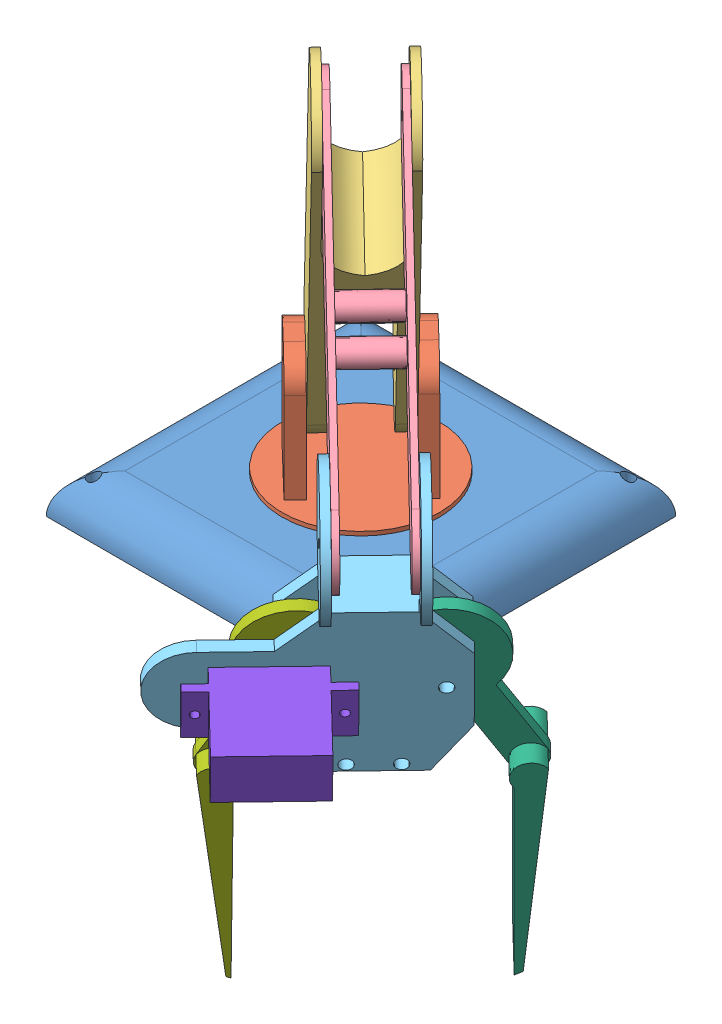
SolidWorks assembly ARM_only, configuration Default. Lengths in mm.
Overall size (206.23 165.3 199.03).
9 component instances, 8 part files, 10 mates.
Components (placement in the parent):
- arm_base-1: arm_base [Default] at (38.6443 32.0455 63.3645) size (80 10 80)
- arm_shoulder-1: arm_shoulder [Default] at (27.657 34.0455 61.3737) x (0.720928 0 0.69301) z (-0.69301 0 0.720928) size (69.78 39 69.78)
- arm_bicep-1: arm_bicep [Default] at (55.5398 114.6682 74.3058) x (0.335057 0.885438 0.322082) z (0.638337 -0.464758 0.613617) size (121.85 20 25)
- Part1-1: Part1 [Default] at (70.0976 157.2638 91.074) x (0.669126 -0.372217 0.643214) z (-0.69301 0 0.720928) size (110 20 16)
- Assem1-1: Assem1 [Default] at (110.584 85.6915 148.7817) x (-0.69301 0 0.720928) z (-0.146392 -0.979166 -0.140723) size (114.11 44.53 126.4)
  - grip2-1: grip2 [Default] at (-23.4355 -8.246 23.6192) size (60 31.06 69.16)
  - Gear 1-1: Gear 1 [Default] at (-23.3605 -0.246 7.4443) x (-0.487316 0 0.873226) z (-0.873226 0 -0.487316) size (88.86 14 39.75)
  - Gear 2-1: Gear 2 [Default] at (4.7269 -0.246 -10.7707) x (-0.369826 0 -0.929101) z (0.929101 0 -0.369826) size (91.37 14 30.68)
  - Servo Motor 6-1: Servo Motor 6 [Default] at (24.4645 -30.246 -7.3808) x (-1 0 0) z (0 0 -1) size (32 27 12)
Mates (geometry in assembly coordinates):
- Coincident1: coincident anti-aligned: plane of arm_base-1 through (27.507 34.0455 61.1684) normal (0 1 0); plane of arm_shoulder-1 through (27.657 34.0455 61.3737) normal (0 -1 0)
- Concentric1: concentric anti-aligned: cylinder of arm_base-1 through (27.657 38.0455 61.3737) axis (0 1 0) radius 20; cylinder of arm_shoulder-1 through (27.657 43.0455 61.3737) axis (0 -1 0) radius 20
- Width1: width anti-aligned: plane of arm_shoulder-1 through (13.5176 73.0455 61.6529) normal (0.69301 0 -0.720928); plane of arm_shoulder-1 through (27.3778 73.0455 47.2344) normal (-0.69301 0 0.720928); plane of arm_bicep-1 through (41.6796 114.6682 88.7243) normal (-0.69301 0 0.720928); plane of arm_bicep-1 through (55.5398 114.6682 74.3058) normal (0.69301 0 -0.720928)
- Concentric2: concentric aligned: cylinder of arm_bicep-1 through (20.7269 66.0455 68.583) axis (0.69301 0 -0.720928) radius 1.5; cylinder of arm_shoulder-1 through (15.8759 66.0455 73.6295) axis (0.69301 0 -0.720928) radius 1.5
- Concentric3: concentric aligned: cylinder of arm_bicep-1 through (20.7269 66.0455 68.583) axis (0.69301 0 -0.720928) radius 1.5; cylinder of arm_shoulder-1 through (15.8759 66.0455 73.6295) axis (0.69301 0 -0.720928) radius 1.5
- Width2: width aligned: plane of arm_bicep-1 through (48.9518 172.4734 92.9407) normal (0.69301 0 -0.720928); plane of arm_bicep-1 through (60.0399 172.4734 81.4058) normal (-0.69301 0 0.720928); plane of Part1-1 through (70.0976 157.2638 91.074) normal (0.69301 0 -0.720928); plane of Part1-1 through (81.1485 136.4363 123.8905) normal (-0.69301 0 0.720928)
- Concentric4: concentric anti-aligned: cylinder of arm_bicep-1 through (52.9974 151.325 99.6038) axis (0.69301 0 -0.720928) radius 1.5; cylinder of Part1-1 through (65.4716 151.325 86.6271) axis (-0.69301 0 0.720928) radius 1.5
- Concentric5: concentric anti-aligned: cylinder of arm_bicep-1 through (52.9974 151.325 99.6038) axis (0.69301 0 -0.720928) radius 1.5; cylinder of Part1-1 through (65.4716 151.325 86.6271) axis (-0.69301 0 0.720928) radius 1.5
- Width3: width anti-aligned: plane of Part1-1 through (70.0976 157.2638 91.074) normal (0.69301 0 -0.720928); plane of Assem1-1/grip2-1 through (81.1485 136.4363 123.8905) normal (-0.69301 0 0.720928); plane of Part1-1 through (109.7841 60.8899 154.3442) normal (-0.69301 0 0.720928); plane of Assem1-1/grip2-1 through (123.7969 60.8899 139.7669) normal (0.69301 0 -0.720928)
- Concentric6: concentric anti-aligned: cylinder of Part1-1 through (125.6929 117.8254 144.5164) axis (-0.69301 0 0.720928) radius 1.5; cylinder of Assem1-1/grip2-1 through (112.602 117.8254 158.1347) axis (0.69301 0 -0.720928) radius 1.5
